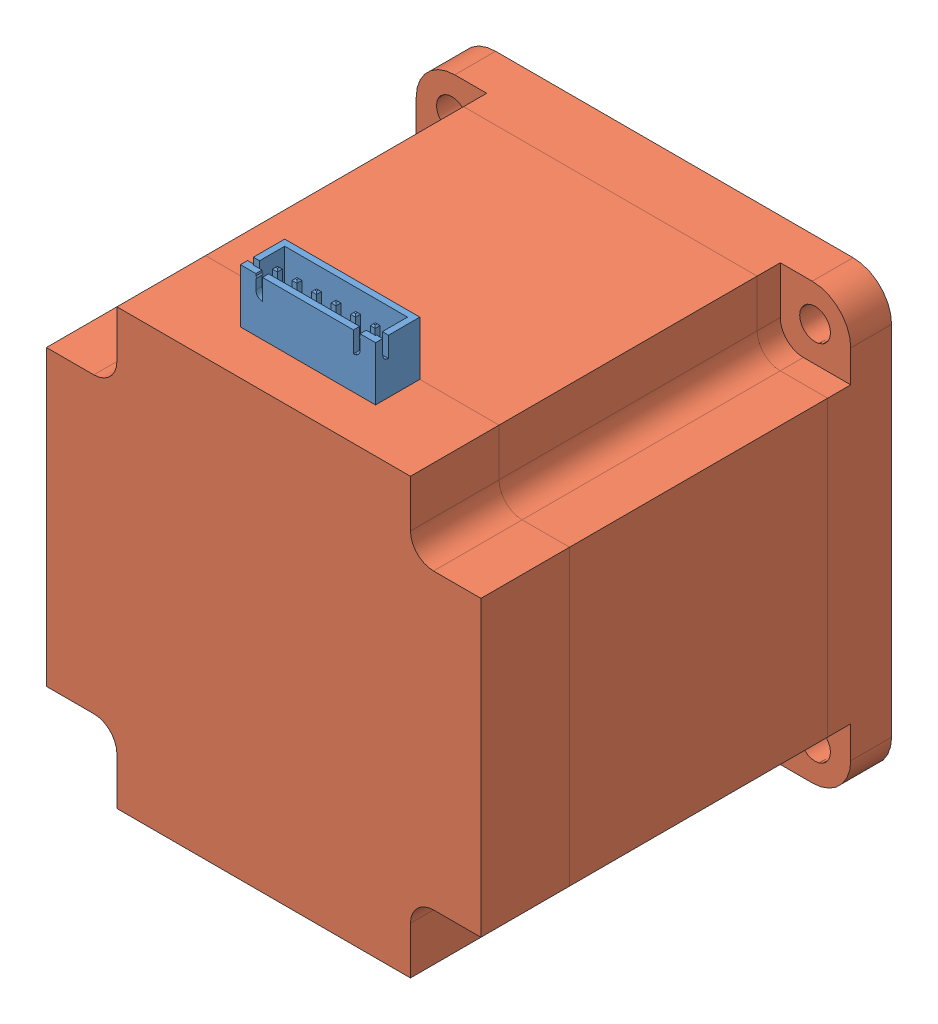
SolidWorks assembly MotorStepper, configuration Predeterminado. Lengths in mm.
Overall size (56.4 63.4 77.3).
2 component instances, 2 part files, 0 mates.
Components (placement in the parent):
- JST XH 6 S6B-XH-A1 shrouded header connector-3: JST XH 6 S6B-XH-A1 shrouded header connector [Default] at (-0.3865 1.9892 17.54) size (17.54 10.45 5.75)
- tapa-3: tapa [Predeterminado] at (-0.3865 -26.2108 -27.135) size (56.4 56.4 77.3)
